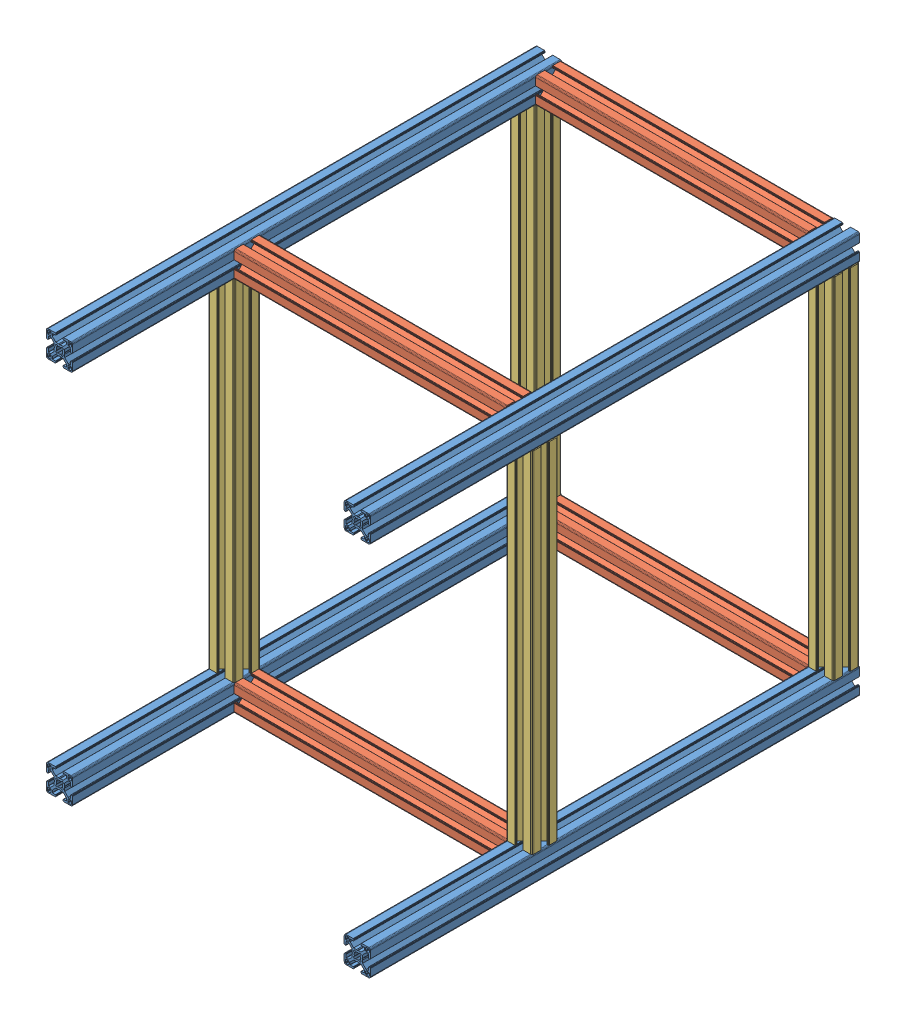
SolidWorks assembly module6_frame_v1.0, configuration Default. Lengths in mm.
Overall size (371 460 560).
12 component instances, 3 part files, 36 mates.
Components (placement in the parent):
- profile_30x30mm_560mm-15: profile_30x30mm_560mm [Default] at origin size (30 30 560)
- profile_30x30mm_560mm-14: profile_30x30mm_560mm [Default] at (341 0 0) size (30 30 560)
- Profile_30x30mm_311mm-19: Profile_30x30mm_311mm [Default] at (341 0 -185) x (0 0 -1) z (1 0 0) size (30 30 311)
- Profile_30x30mm_311mm-18: Profile_30x30mm_311mm [Default] at (341 0 -530) x (0 0 -1) z (1 0 0) size (30 30 311)
- Profile_30x30mm_400mm-22: Profile_30x30mm_400mm [Default] at (0 30 -560) x (1 0 0) z (0 -1 0) size (30 30 400)
- Profile_30x30mm_400mm-20: Profile_30x30mm_400mm [Default] at (341 30 -560) x (1 0 0) z (0 -1 0) size (30 30 400)
- profile_30x30mm_560mm-12: profile_30x30mm_560mm [Default] at (341 430 0) size (30 30 560)
- profile_30x30mm_560mm-13: profile_30x30mm_560mm [Default] at (0 430 0) size (30 30 560)
- Profile_30x30mm_311mm-17: Profile_30x30mm_311mm [Default] at (341 430 -560) x (0 1 0) z (1 0 0) size (30 30 311)
- Profile_30x30mm_311mm-16: Profile_30x30mm_311mm [Default] at (30 460 -185) x (0 0 -1) z (-1 0 0) size (30 30 311)
- Profile_30x30mm_400mm-23: Profile_30x30mm_400mm [Default] at (371 430 -215) x (-1 0 0) z (0 1 0) size (30 30 400)
- Profile_30x30mm_400mm-24: Profile_30x30mm_400mm [Default] at (30 430 -185) x (0 0 -1) z (0 1 0) size (30 30 400)
Mates (geometry in assembly coordinates):
- Coincident1: coincident: plane of assembly; plane of assembly; plane of profile_30x30mm_560mm-15 through (0 0 0) normal (0 1 0); plane of profile_30x30mm_560mm-14 through (341 0 0) normal (0 1 0)
- Coincident2: coincident: plane of assembly; plane of assembly; plane of profile_30x30mm_560mm-15 through (0 0 0) normal (0 0 1); plane of profile_30x30mm_560mm-14 through (341 0 0) normal (0 0 1)
- Coincident4: coincident: plane of assembly through (0 0 0) normal (0 1 0); plane of Profile_30x30mm_311mm-19 through (341 0 -185) normal (0 1 0); plane of assembly
- Coincident5: coincident: plane of assembly; plane of assembly; plane of profile_30x30mm_560mm-14 through (341 10.25 -560) normal (-1 0 0); plane of Profile_30x30mm_311mm-19 through (341 0 -185) normal (1 0 0)
- Coincident44: coincident: plane of Profile_30x30mm_311mm-19 through (341 0 -185) normal (0 0 -1); plane of ? through (2 180 -185) normal (0 0 1)
- Coincident7: coincident: plane of assembly through (0 0 0) normal (0 1 0); plane of Profile_30x30mm_311mm-18 through (341 0 -530) normal (0 1 0); plane of assembly
- Distance3: distance = 530 mm: plane of assembly through (0 0 0) normal (0 0 1); plane of Profile_30x30mm_311mm-18 through (341 0 -530) normal (0 0 -1); plane of assembly
- Coincident9: coincident: plane of assembly; plane of assembly; plane of profile_30x30mm_560mm-14 through (341 28 -560) normal (-1 0 0); plane of Profile_30x30mm_311mm-18 through (341 0 -530) normal (1 0 0)
- Coincident10: coincident: plane of assembly; plane of assembly; plane of profile_30x30mm_560mm-15 through (28 30 -560) normal (0 1 0); plane of Profile_30x30mm_400mm-22 through (0 30 -560) normal (0 -1 0)
- Coincident11: coincident: plane of assembly; plane of assembly; plane of profile_30x30mm_560mm-15 through (0 0 -560) normal (0 0 -1); plane of Profile_30x30mm_400mm-22 through (0 30 -560) normal (0 0 1)
- Coincident12: coincident: plane of assembly; plane of assembly; plane of profile_30x30mm_560mm-15 through (0 10.25 -560) normal (-1 0 0); plane of Profile_30x30mm_400mm-22 through (0 430 -549.75) normal (-1 0 0)
- Coincident15: coincident: plane of Profile_30x30mm_400mm-22 through (0 30 -560) normal (1 0 0); plane of ? through (0 580 -185) normal (1 0 0)
- Distance6: distance = 550 mm: plane of ? through (0 580 -185) normal (0 1 0); plane of Profile_30x30mm_400mm-22 through (0 30 -560) normal (0 -1 0)
- Coincident21: coincident: plane of assembly; plane of assembly; plane of profile_30x30mm_560mm-14 through (369 30 -560) normal (0 1 0); plane of Profile_30x30mm_400mm-20 through (341 30 -560) normal (0 -1 0)
- Coincident22: coincident: plane of assembly; plane of assembly; plane of Profile_30x30mm_311mm-18 through (30 2 -560) normal (0 0 -1); plane of Profile_30x30mm_400mm-20 through (341 30 -560) normal (0 0 1)
- Coincident23: coincident: plane of assembly; plane of assembly; plane of profile_30x30mm_560mm-14 through (371 19.75 -560) normal (1 0 0); plane of Profile_30x30mm_400mm-20 through (371 430 -558) normal (1 0 0)
- Coincident24: coincident: plane of assembly; plane of assembly; plane of Profile_30x30mm_400mm-20 through (341 430 -560) normal (0 1 0); plane of profile_30x30mm_560mm-12 through (360.75 430 -560) normal (0 -1 0)
- Coincident25: coincident: plane of assembly; plane of assembly; plane of Profile_30x30mm_400mm-20 through (371 430 -540.25) normal (1 0 0); plane of profile_30x30mm_560mm-12 through (371 432 -560) normal (1 0 0)
- Coincident26: coincident: plane of assembly; plane of assembly; plane of Profile_30x30mm_400mm-20 through (343 430 -560) normal (0 0 -1); plane of profile_30x30mm_560mm-12 through (341 430 -560) normal (0 0 -1)
- Coincident27: coincident: plane of assembly; plane of assembly; plane of Profile_30x30mm_400mm-22 through (0 430 -560) normal (0 1 0); plane of profile_30x30mm_560mm-13 through (19.75 430 -560) normal (0 -1 0)
- Coincident28: coincident: plane of assembly; plane of assembly; plane of Profile_30x30mm_400mm-22 through (2 430 -560) normal (0 0 -1); plane of profile_30x30mm_560mm-13 through (0 430 -560) normal (0 0 -1)
- Coincident29: coincident: plane of assembly; plane of assembly; plane of Profile_30x30mm_400mm-22 through (0 430 -532) normal (-1 0 0); plane of profile_30x30mm_560mm-13 through (0 440.25 -560) normal (-1 0 0)
- Coincident30: coincident: plane of assembly; plane of assembly; plane of profile_30x30mm_560mm-13 through (30 449.75 -560) normal (1 0 0); plane of Profile_30x30mm_311mm-17 through (30 430 -560) normal (-1 0 0)
- Coincident31: coincident: plane of assembly; plane of assembly; plane of profile_30x30mm_560mm-13 through (0 430 -560) normal (0 0 -1); plane of Profile_30x30mm_311mm-17 through (30 432 -560) normal (0 0 -1)
- Coincident32: coincident: plane of assembly; plane of assembly; plane of profile_30x30mm_560mm-12 through (351.25 460 -560) normal (0 1 0); plane of Profile_30x30mm_311mm-17 through (30 460 -558) normal (0 1 0)
- Coincident36: coincident: plane of assembly; plane of assembly; plane of profile_30x30mm_560mm-13 through (30 449.75 -560) normal (1 0 0); plane of Profile_30x30mm_311mm-16 through (30 460 -185) normal (-1 0 0)
- Coincident37: coincident: plane of assembly; plane of assembly; plane of profile_30x30mm_560mm-13 through (10.25 460 -560) normal (0 1 0); plane of Profile_30x30mm_311mm-16 through (341 460 -204.75) normal (0 1 0)
- Distance9: distance = 185 mm: plane of assembly; plane of assembly; plane of profile_30x30mm_560mm-12 through (341 430 0) normal (0 0 1); plane of Profile_30x30mm_311mm-16 through (341 432 -185) normal (0 0 1)
- Coincident43: coincident: plane of ? through (2 180 -185) normal (0 0 1); plane of Profile_30x30mm_311mm-16 through (341 432 -185) normal (0 0 1)
- Coincident61: coincident: plane of ? through (2 180 -185) normal (0 0 1); plane of Profile_30x30mm_400mm-23 through (343 30 -185) normal (0 0 1)
- Coincident62: coincident: plane of assembly; plane of assembly; plane of profile_30x30mm_560mm-14 through (369 30 -560) normal (0 1 0); plane of Profile_30x30mm_400mm-23 through (371 30 -215) normal (0 -1 0)
- Coincident63: coincident: plane of assembly; plane of assembly; plane of profile_30x30mm_560mm-14 through (371 19.75 -560) normal (1 0 0); plane of Profile_30x30mm_400mm-23 through (371 30 -187) normal (1 0 0)
- Coincident64: coincident: plane of assembly; plane of assembly; plane of profile_30x30mm_560mm-12 through (341 458 -560) normal (-1 0 0); plane of Profile_30x30mm_311mm-17 through (341 430 -560) normal (1 0 0)
- Coincident65: coincident: plane of assembly; plane of assembly; plane of Profile_30x30mm_311mm-19 through (30 2 -215) normal (0 0 -1); plane of Profile_30x30mm_400mm-24 through (10.25 30 -215) normal (0 0 -1)
- Coincident66: coincident: plane of assembly; plane of assembly; plane of profile_30x30mm_560mm-15 through (0 28 -560) normal (-1 0 0); plane of Profile_30x30mm_400mm-24 through (0 30 -195.25) normal (-1 0 0)
- Coincident67: coincident: plane of assembly; plane of assembly; plane of profile_30x30mm_560mm-15 through (10.25 30 -560) normal (0 1 0); plane of Profile_30x30mm_400mm-24 through (30 30 -185) normal (0 -1 0)
